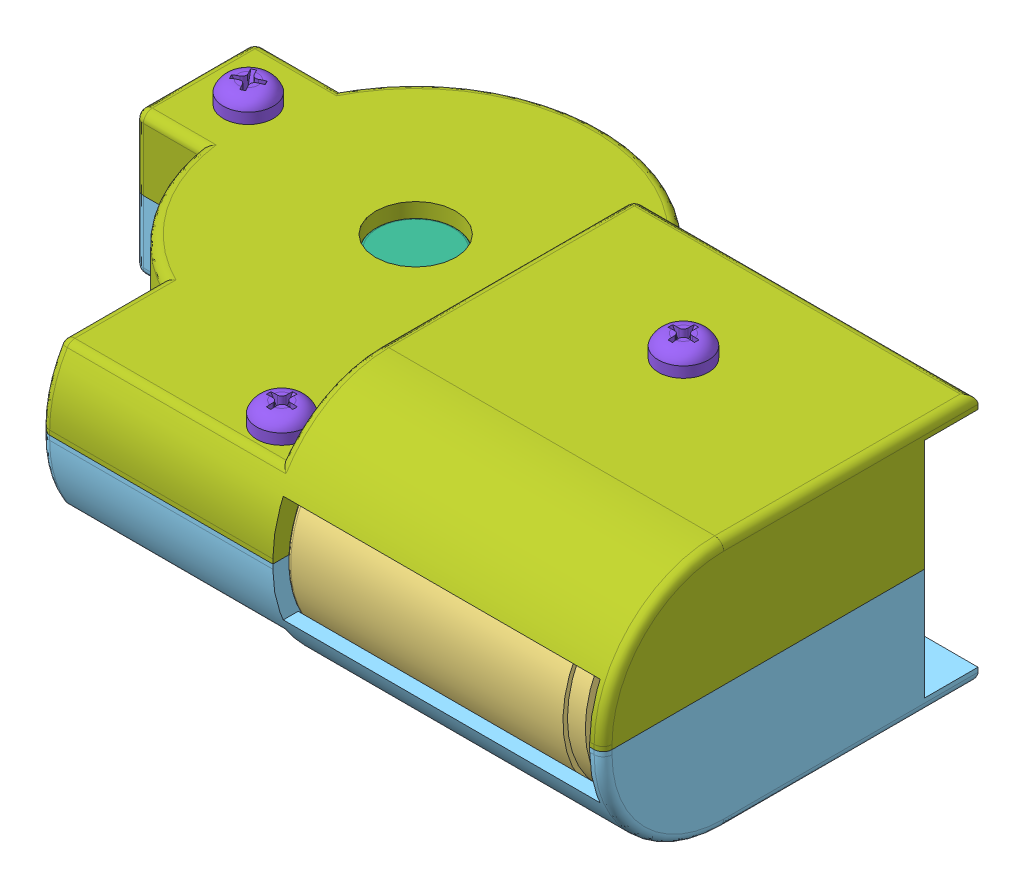
SolidWorks assembly Motor (left), configuration Default. Lengths in mm.
Overall size (81 42.94 53).
15 component instances, 8 part files, 0 mates.
Components (placement in the parent):
- Motor (left).step-1: Motor (left).step [Default] at origin size (81 42.94 53)
  - Drivning_sub_assembly_vanster_ojaobz-5.step-1: Drivning_sub_assembly_vanster_ojaobz-5.step [Default] at (359.1405 -88.75 363.0147) x (0 0 -1) z (0 1 0) size (53 81 42.94)
    - Planetbararaxel_ojaobz-5.step-1: Planetbararaxel_ojaobz-5.step [Default] at (343.5147 326.1417 9.5) x (-0.999909 0.013506 0) z (0 0 -1) size (20 20 26)
    - Planethjul_ojaobz-5.step-1: Planethjul_ojaobz-5.step [Default] at (349.0885 331.5669 9.5) x (0.33611 -0.941823 0) z (0 0 1) size (8.23 8.46 4)
    - Planethjul_ojaobz-5.step-2: Planethjul_ojaobz-5.step [Default] at (348.9399 320.5679 13.5) x (-0.820778 0.571247 0) z (0 0 -1) size (8.23 8.46 4)
    - Planethjul_ojaobz-5.step-3: Planethjul_ojaobz-5.step [Default] at (338.0895 331.7155 9.5) x (0.33611 -0.941823 0) z (0 0 1) size (8.23 8.46 4)
    - Planethjul_ojaobz-5.step-4: Planethjul_ojaobz-5.step [Default] at (337.9409 320.7165 9.5) x (0.33611 -0.941823 0) z (0 0 1) size (8.23 8.46 4)
    - Motor_drivning_ojaobz-5.step-1: Motor_drivning_ojaobz-5.step [Default] at (325.0147 279.1417 13.5) x (0 0 -1) z (0 1 0) size (24 32.5 40)
    - Snackskruv_drivning_ojaobz-5.step-1: Snackskruv_drivning_ojaobz-5.step [Default] at (325.0147 311.6417 13.5) x (0 0 -1) z (0 1 0) size (7.5 7.5 20.7)
    - Drivkapa_B_vanster_ojaobz-5.step-1: Drivkapa_B_vanster_ojaobz-5.step [Default] at (311.5147 273.1417 0) size (53 81 20.5)
    - Snackhjul_drivning_ojaobz-5.step-1: Snackhjul_drivning_ojaobz-5.step [Default] at (343.5147 326.1417 16.5) x (0.000821 -1 0) z (0 0 -1) size (33.93 33.93 10)
    - Drivkapa_A_vanster_ojaobz-5.step-1: Drivkapa_A_vanster_ojaobz-5.step [Default] at (311.5147 273.1417 28) x (-1 0 0) z (0 0 -1) size (53 81 14)
    - Skruv_blank_10_ojaobz-5.step-1: Skruv_blank_10_ojaobz-5.step [Default] at (317.5147 315.1417 22) x (0 -1 0) z (0 0 -1) size (5.6 5.6 11.94)
    - Skruv_blank_10_ojaobz-5.step-2: Skruv_blank_10_ojaobz-5.step [Default] at (340.5147 293.1417 28) x (1 0 0) z (0 0 -1) size (5.6 5.6 11.94)
    - Skruv_blank_10_ojaobz-5.step-3: Skruv_blank_10_ojaobz-5.step [Default] at (346.7647 348.1417 22) x (-0.884048 -0.467396 0) z (0 0 -1) size (5.6 5.6 11.94)
